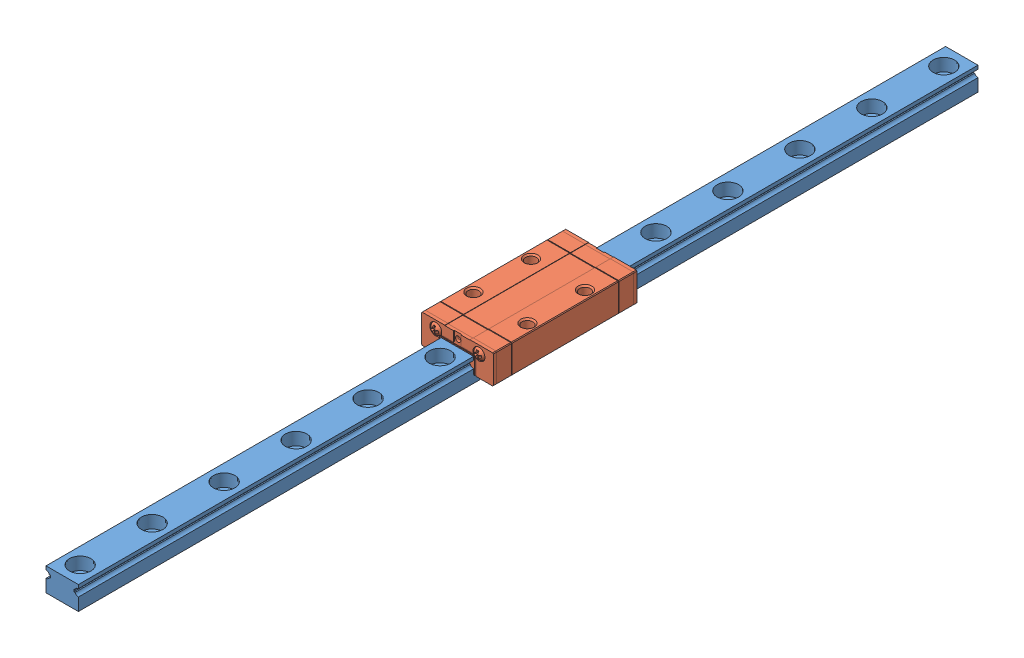
SolidWorks assembly Assem1, configuration По умолчанию. Lengths in mm.
Overall size (20 10 250).
2 component instances, 2 part files, 2 mates.
Components (placement in the parent):
- v1_MGN9_250-1: v1_MGN9_250 [По умолчанию] at origin size (9 6.5 250)
- v1_MGN9-H-1: v1_MGN9-H [По умолчанию] at (0 2.75 120.2219) size (20 8 41.29)
Mates (geometry in assembly coordinates):
- Coincident1: coincident anti-aligned: plane of v1_MGN9_250-1 through (-4.5 3.25 250) normal (0 1 0); plane of v1_MGN9-H-1 through (0 3.25 135.1719) normal (0 -1 0)
- Coincident2: coincident anti-aligned: plane of v1_MGN9_250-1 through (-4.5 -3.25 250) normal (-1 0 0); plane of v1_MGN9-H-1 through (-4.5 2.75 135.1719) normal (1 0 0)
